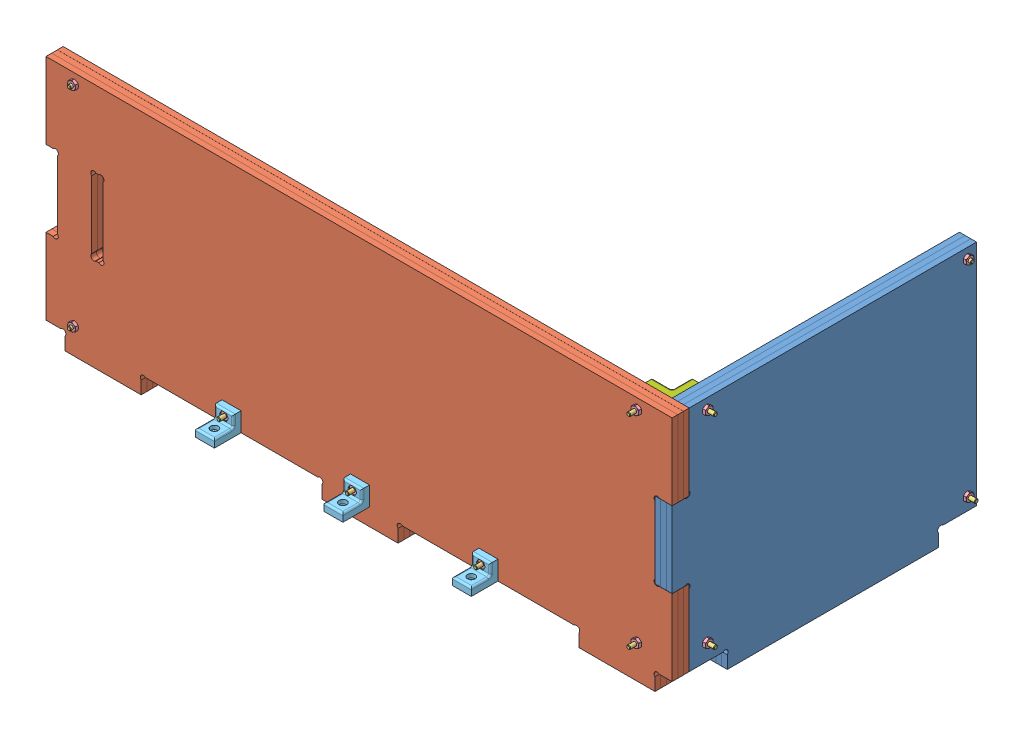
SolidWorks assembly mur-complet, configuration Défaut. Lengths in mm.
Overall size (334 129.04 174).
34 component instances, 8 part files, 87 mates.
Components (placement in the parent):
- mur_cote-1: mur_cote [Défaut] at origin size (3 129 160)
- mur_cote-2: mur_cote [Défaut] at (3 0 0) size (3 129 160)
- mur_cote-3: mur_cote [Défaut] at (6 0 0) size (3 129 160)
- grand_mur_devant-1: grand_mur_devant [Défaut] at (9 -0.0357 -3) x (-1 0 0) z (0 0 -1) size (329 129 3)
- grand_mur_devant-2: grand_mur_devant [Défaut] at (9 0 -6) x (-1 0 0) z (0 0 -1) size (329 129 3)
- grand_mur_devant-3: grand_mur_devant [Défaut] at (9 -0.0357 0) x (-1 0 0) z (0 0 -1) size (329 129 3)
- vis-chc-1: vis-chc [Vis CHC M2x12] at (-305 14 -9) x (1 0 0) z (0 1 0) size (3.8 14 3.8)
- ecrou-h-1: ecrou-h [6007 HU M2] at (-305 14 1.6) x (1 0 0) z (0 -1 0) size (4 1.6 4.62)
- vis-chc-2: vis-chc [Vis CHC M2x16] at (-9 124 -11) x (0.964192 -0.265205 0) z (0.265205 0.964192 0) size (3.8 18 3.8)
- vis-chc-3: vis-chc [Vis CHC M2x16] at (-2 124 -18) x (0 -0.924225 -0.381849) z (0 0.381849 -0.924225) size (3.8 18 3.8)
- vis-chc-4: vis-chc [Vis CHC M2x16] at (-222.5 16 -9) x (0.991602 0.129329 0) z (-0.129329 0.991602 0) size (3.8 18 3.8)
- vis-chc-5: vis-chc [Vis CHC M2x16] at (-155 16 -9) x (0.999985 0.005521 0) z (-0.005521 0.999985 0) size (3.8 18 3.8)
- vis-chc-6: vis-chc [Vis CHC M2x16] at (-87.5 16 -9) x (0.879517 -0.475868 0) z (0.475868 0.879517 0) size (3.8 18 3.8)
- ecrou-h-2: ecrou-h [6007 HU M2] at (10.6 124 -18) x (0 -0.866025 0.5) z (0 0.5 0.866025) size (4 1.6 4.62)
- ecrou-h-3: ecrou-h [6007 HU M2] at (-9 124 1.6) x (1 0 0) z (0 -1 0) size (4 1.6 4.62)
- ecrou-h-4: ecrou-h [6007 HU M2] at (-87.5 16 3.6) x (0.866025 -0.5 0) z (-0.5 -0.866025 0) size (4 1.6 4.62)
- ecrou-h-5: ecrou-h [6007 HU M2] at (-155 16 3.6) x (0.866025 -0.5 0) z (-0.5 -0.866025 0) size (4 1.6 4.62)
- ecrou-h-6: ecrou-h [6007 HU M2] at (-222.5 16 3.6) x (0 -1 0) z (-1 0 0) size (4 1.6 4.62)
- vis-chc-7: vis-chc [Vis CHC M2x16] at (-9 18 -11) x (-0.417392 -0.908727 0) z (0.908727 -0.417392 0) size (3.8 18 3.8)
- vis-chc-8: vis-chc [Vis CHC M2x16] at (-2 18 -18) x (0 -0.924225 -0.381849) z (0 0.381849 -0.924225) size (3.8 18 3.8)
- ecrou-h-7: ecrou-h [6007 HU M2] at (10.6 18 -18) x (0 0 1) z (0 1 0) size (4 1.6 4.62)
- ecrou-h-8: ecrou-h [6007 HU M2] at (-9 18 1.6) x (-1 0 0) z (0 1 0) size (4 1.6 4.62)
- equerre-ecrou-1: equerre-ecrou [Défaut] at (-222.5 8.9643 0) size (10 10 14)
- equerre-ecrou-2: equerre-ecrou [Défaut] at (-155 8.9643 0) size (10 10 14)
- equerre-ecrou-3: equerre-ecrou [Défaut] at (-87.5 8.9643 0) size (10 10 14)
- equerre-4: equerre [Défaut] at (0 9 -155) x (0 0 1) z (-1 0 0) size (10 10 14)
- coin-1: coin [Défaut] at (0 124 -9) x (0 1 0) z (-1 0 0) size (10 14 14)
- coin-tri-1: coin-tri [Défaut] at (0 9 -18) x (0 0 1) z (-1 0 0) size (14 14 14)
- vis-chc-9: vis-chc [Vis CHC M2x16] at (-2 16 -155) x (0 -0.924225 -0.381849) z (0 0.381849 -0.924225) size (3.8 18 3.8)
- vis-chc-10: vis-chc [Vis CHC M2x12] at (0 124 -155) x (0 0 -1) z (0 1 0) size (3.8 14 3.8)
- ecrou-h-9: ecrou-h [6007 HU M2] at (10.6 16 -155) x (0 0 -1) z (0 -1 0) size (4 1.6 4.62)
- ecrou-h-10: ecrou-h [6007 HU M2] at (10.6 124 -155) x (0 0 -1) z (0 -1 0) size (4 1.6 4.62)
- ecrou-h-11: ecrou-h [6007 HU M2] at (-305 124 1.6) x (1 0 0) z (0 -1 0) size (4 1.6 4.62)
- vis-chc-11: vis-chc [Vis CHC M2x12] at (-305 124 -9) x (0.964192 -0.265205 0) z (0.265205 0.964192 0) size (3.8 14 3.8)
Mates (geometry in assembly coordinates):
- Coïncidente1: coincident anti-aligned: plane of mur_cote-1 through (3 7.8686 -141.1314) normal (1 0 0); plane of mur_cote-2 through (3 7.8686 -141.1314) normal (-1 0 0)
- Coïncidente2: coincident aligned: plane of mur_cote-1 through (3 129 -9) normal (0 1 0); plane of mur_cote-2 through (6 129 -9) normal (0 1 0)
- Coïncidente3: coincident aligned: plane of mur_cote-1 through (3 91.2627 -9) normal (0 0 1); plane of mur_cote-2 through (6 91.2627 -9) normal (0 0 1)
- Coïncidente4: coincident anti-aligned: plane of mur_cote-2 through (6 7.8686 -141.1314) normal (1 0 0); plane of mur_cote-3 through (6 7.8686 -141.1314) normal (-1 0 0)
- Coïncidente5: coincident aligned: plane of mur_cote-2 through (6 129 -9) normal (0 1 0); plane of mur_cote-3 through (9 129 -9) normal (0 1 0)
- Coïncidente6: coincident aligned: plane of mur_cote-2 through (6 49 0) normal (0 0 1); plane of mur_cote-3 through (9 49 0) normal (0 0 1)
- Coïncidente25: coincident anti-aligned: plane of mur_cote-1 through (3 91.2627 -9) normal (0 0 1); plane of grand_mur_devant-2 through (1.1314 87.8686 -9) normal (0 0 -1)
- Coïncidente26: coincident aligned: plane of mur_cote-3 through (9 129 -9) normal (0 1 0); plane of grand_mur_devant-2 through (-320 129 -9) normal (0 1 0)
- Coïncidente27: coincident aligned: plane of mur_cote-3 through (9 7.8686 -141.1314) normal (1 0 0); plane of grand_mur_devant-2 through (9 129 -9) normal (1 0 0)
- Coïncidente29: coincident anti-aligned: plane of grand_mur_devant-1 through (1.1314 87.833 -6) normal (0 0 -1); plane of grand_mur_devant-2 through (1.1314 87.8686 -6) normal (0 0 1)
- Coïncidente30: coincident aligned: plane of grand_mur_devant-1 through (9 128.9643 -6) normal (1 0 0); plane of grand_mur_devant-2 through (9 129 -9) normal (1 0 0)
- Coïncidente31: coincident aligned: plane of grand_mur_devant-1 through (9 128.9643 -6) normal (1 0 0); plane of grand_mur_devant-3 through (9 128.9643 -3) normal (1 0 0)
- Coïncidente32: coincident anti-aligned: plane of grand_mur_devant-1 through (1.1314 87.833 -3) normal (0 0 1); plane of grand_mur_devant-3 through (1.1314 87.833 -3) normal (0 0 -1)
- Coïncidente33: coincident aligned: plane of grand_mur_devant-1 through (0 -0.0357 -6) normal (0 -1 0); plane of grand_mur_devant-3 through (0 -0.0357 -3) normal (0 -1 0)
- Coaxiale1: concentric anti-aligned: cylinder of grand_mur_devant-2 through (-305 14 -9) axis (0 0 1) radius 1; cylinder of vis-chc-1 through (-305 14 3) axis (0 0 -1) radius 1
- Coïncidente34: coincident anti-aligned: plane of grand_mur_devant-2 through (1.1314 87.8686 -9) normal (0 0 -1); plane of vis-chc-1 through (-305 14 -9) normal (0 0 1)
- Coaxiale2: concentric anti-aligned: cylinder of vis-chc-1 through (-305 14 3) axis (0 0 -1) radius 1; cylinder of ecrou-h-1 through (-305 14 0) axis (0 0 1) radius 0.7835
- Coïncidente35: coincident anti-aligned: plane of grand_mur_devant-3 through (1.1314 87.833 0) normal (0 0 1); plane of ecrou-h-1 through (-303 15.1547 0) normal (0 0 -1)
- Parallèle1: parallel aligned: plane of grand_mur_devant-3 through (-320 8.9643 -3) normal (-1 0 0); plane of ecrou-h-1 through (-307 15.1547 0) normal (-1 0 0)
- Coïncidente37: coincident anti-aligned: plane of grand_mur_devant-3 through (1.1314 87.833 0) normal (0 0 1); plane of equerre-ecrou-1 through (-222.5 8.9643 0) normal (0 0 -1)
- Coïncidente38: coincident anti-aligned: plane of grand_mur_devant-3 through (1.1314 87.833 0) normal (0 0 1); plane of equerre-ecrou-2 through (-155 8.9643 0) normal (0 0 -1)
- Coïncidente39: coincident anti-aligned: plane of grand_mur_devant-3 through (1.1314 87.833 0) normal (0 0 1); plane of equerre-ecrou-3 through (-87.5 8.9643 0) normal (0 0 -1)
- Coïncidente40: coincident anti-aligned: plane of mur_cote-1 through (0 7.8686 -141.1314) normal (-1 0 0); plane of equerre-4 through (0 9 -155) normal (1 0 0)
- Coaxiale3: concentric anti-aligned: cylinder of mur_cote-1 through (0 16 -155) axis (1 0 0) radius 1; cylinder of equerre-4 through (0 16 -155) axis (-1 0 0) radius 1
- Coaxiale4: concentric aligned: cylinder of grand_mur_devant-3 through (-222.5 15.9643 -3) axis (0 0 1) radius 1; cylinder of equerre-ecrou-1 through (-222.5 15.9643 0) axis (0 0 1) radius 1
- Coaxiale5: concentric aligned: cylinder of grand_mur_devant-3 through (-155 15.9643 -3) axis (0 0 1) radius 1; cylinder of equerre-ecrou-2 through (-155 15.9643 0) axis (0 0 1) radius 1
- Coaxiale6: concentric aligned: cylinder of grand_mur_devant-3 through (-87.5 15.9643 -3) axis (0 0 1) radius 1; cylinder of equerre-ecrou-3 through (-87.5 15.9643 0) axis (0 0 1) radius 1
- Coïncidente42: coincident aligned: plane of grand_mur_devant-3 through (-177.2627 8.9643 -3) normal (0 -1 0); plane of equerre-ecrou-1 through (-227.5 8.9643 4) normal (0 -1 0)
- Coïncidente43: coincident aligned: plane of grand_mur_devant-3 through (-177.2627 8.9643 -3) normal (0 -1 0); plane of equerre-ecrou-2 through (-160 8.9643 4) normal (0 -1 0)
- Coïncidente44: coincident aligned: plane of grand_mur_devant-3 through (-42.2627 8.9643 -3) normal (0 -1 0); plane of equerre-ecrou-3 through (-92.5 8.9643 4) normal (0 -1 0)
- Coïncidente45: coincident aligned: plane of mur_cote-1 through (3 9 -160) normal (0 -1 0); plane of equerre-4 through (-4 9 -160) normal (0 -1 0)
- Coïncidente46: coincident anti-aligned: plane of grand_mur_devant-2 through (1.1314 87.8686 -9) normal (0 0 -1); plane of coin-1 through (-4 119 -9) normal (0 0 1)
- Coïncidente47: coincident anti-aligned: plane of mur_cote-1 through (0 7.8686 -141.1314) normal (-1 0 0); plane of coin-1 through (0 124 -9) normal (1 0 0)
- Coïncidente49: coincident aligned: plane of mur_cote-1 through (3 129 -9) normal (0 1 0); plane of coin-1 through (-4 129 -23) normal (0 1 0)
- Coaxiale7: concentric anti-aligned: cylinder of grand_mur_devant-2 through (-222.5 16 -9) axis (0 0 1) radius 1; cylinder of vis-chc-4 through (-222.5 16 7) axis (0 0 -1) radius 1
- Coaxiale8: concentric anti-aligned: cylinder of grand_mur_devant-2 through (-155 16 -9) axis (0 0 1) radius 1; cylinder of vis-chc-5 through (-155 16 7) axis (0 0 -1) radius 1
- Coaxiale9: concentric anti-aligned: cylinder of grand_mur_devant-2 through (-87.5 16 -9) axis (0 0 1) radius 1; cylinder of vis-chc-6 through (-87.5 16 7) axis (0 0 -1) radius 1
- Coïncidente50: coincident anti-aligned: plane of grand_mur_devant-2 through (1.1314 87.8686 -9) normal (0 0 -1); plane of vis-chc-4 through (-222.5 16 -9) normal (0 0 1)
- Coïncidente51: coincident anti-aligned: plane of grand_mur_devant-2 through (1.1314 87.8686 -9) normal (0 0 -1); plane of vis-chc-5 through (-155 16 -9) normal (0 0 1)
- Coïncidente52: coincident anti-aligned: plane of grand_mur_devant-2 through (1.1314 87.8686 -9) normal (0 0 -1); plane of vis-chc-6 through (-87.5 16 -9) normal (0 0 1)
- Coaxiale10: concentric anti-aligned: cylinder of vis-chc-4 through (-222.5 16 7) axis (0 0 -1) radius 1; cylinder of ecrou-h-6 through (-222.5 16 2) axis (0 0 1) radius 0.7835
- Coaxiale11: concentric anti-aligned: cylinder of vis-chc-5 through (-155 16 7) axis (0 0 -1) radius 1; cylinder of ecrou-h-5 through (-155 16 2) axis (0 0 1) radius 0.7835
- Coaxiale12: concentric anti-aligned: cylinder of vis-chc-6 through (-87.5 16 7) axis (0 0 -1) radius 1; cylinder of ecrou-h-4 through (-87.5 16 2) axis (0 0 1) radius 0.7835
- Coïncidente53: coincident anti-aligned: plane of equerre-ecrou-1 through (-220.17 15.9643 2) normal (-0.866025 -0.5 0); plane of ecrou-h-6 through (-220.1906 16 2) normal (0.866025 0.5 0)
- Coïncidente54: coincident anti-aligned: plane of equerre-ecrou-2 through (-156.165 17.9822 2) normal (0.866025 -0.5 0); plane of ecrou-h-5 through (-156.1547 18 2) normal (-0.866025 0.5 0)
- Parallèle2: parallel anti-aligned: plane of equerre-ecrou-3 through (-86.335 13.9465 2) normal (-0.866025 0.5 0); plane of ecrou-h-4 through (-86.3453 14 2) normal (0.866025 -0.5 0)
- Coïncidente56: coincident anti-aligned: plane of equerre-ecrou-3 through (-87.5 8.9643 2) normal (0 0 1); plane of ecrou-h-4 through (-85.1906 16 2) normal (0 0 -1)
- Coïncidente57: coincident anti-aligned: plane of equerre-ecrou-2 through (-155 8.9643 2) normal (0 0 1); plane of ecrou-h-5 through (-152.6906 16 2) normal (0 0 -1)
- Coïncidente58: coincident anti-aligned: plane of equerre-ecrou-1 through (-222.5 8.9643 2) normal (0 0 1); plane of ecrou-h-6 through (-221.3453 14 2) normal (0 0 -1)
- Coaxiale13: concentric aligned: cylinder of coin-1 through (0 124 -18) axis (-1 0 0) radius 1; cylinder of vis-chc-3 through (14 124 -18) axis (-1 0 0) radius 1
- Coïncidente59: coincident anti-aligned: plane of coin-1 through (-2 124 -18) normal (-1 0 0); plane of vis-chc-3 through (-2 124 -18) normal (1 0 0)
- Coaxiale14: concentric aligned: cylinder of coin-1 through (-9 124 -9) axis (0 0 -1) radius 1; cylinder of vis-chc-2 through (-9 124 5) axis (0 0 -1) radius 1
- Coïncidente60: coincident anti-aligned: plane of coin-1 through (-9 124 -11) normal (0 0 -1); plane of vis-chc-2 through (-9 124 -11) normal (0 0 1)
- Coaxiale15: concentric anti-aligned: cylinder of vis-chc-2 through (-9 124 5) axis (0 0 -1) radius 1; cylinder of ecrou-h-3 through (-9 124 0) axis (0 0 1) radius 0.7835
- Coïncidente62: coincident anti-aligned: plane of grand_mur_devant-3 through (1.1314 87.833 0) normal (0 0 1); plane of ecrou-h-3 through (-7 125.1547 0) normal (0 0 -1)
- Parallèle4: parallel aligned: plane of grand_mur_devant-3 through (9 128.9643 -3) normal (1 0 0); plane of ecrou-h-3 through (-7 122.8453 0) normal (1 0 0)
- Coaxiale16: concentric anti-aligned: cylinder of vis-chc-3 through (14 124 -18) axis (-1 0 0) radius 1; cylinder of ecrou-h-2 through (9 124 -18) axis (1 0 0) radius 0.7835
- Coïncidente64: coincident anti-aligned: plane of mur_cote-3 through (9 7.8686 -141.1314) normal (1 0 0); plane of ecrou-h-2 through (9 121.6906 -18) normal (-1 0 0)
- Parallèle5: parallel aligned: plane of grand_mur_devant-3 through (1.1314 87.833 0) normal (0 0 1); plane of ecrou-h-2 through (9 125.1547 -16) normal (0 0 1)
- Coïncidente66: coincident anti-aligned: plane of mur_cote-1 through (0 7.8686 -141.1314) normal (-1 0 0); plane of coin-tri-1 through (0 9 -18) normal (1 0 0)
- Coïncidente67: coincident anti-aligned: plane of grand_mur_devant-2 through (1.1314 87.8686 -9) normal (0 0 -1); plane of coin-tri-1 through (0 9 -9) normal (0 0 1)
- Coïncidente69: coincident aligned: plane of mur_cote-1 through (3 9 -26.7373) normal (0 -1 0); plane of coin-tri-1 through (-4 9 -23) normal (0 -1 0)
- Coaxiale17: concentric aligned: cylinder of coin-tri-1 through (-9 18 -9) axis (0 0 -1) radius 1; cylinder of vis-chc-7 through (-9 18 5) axis (0 0 -1) radius 1
- Coïncidente70: coincident anti-aligned: plane of coin-tri-1 through (-9 18 -11) normal (0 0 -1); plane of vis-chc-7 through (-9 18 -11) normal (0 0 1)
- Coaxiale18: concentric aligned: cylinder of coin-tri-1 through (0 18 -18) axis (-1 0 0) radius 1; cylinder of vis-chc-8 through (14 18 -18) axis (-1 0 0) radius 1
- Coïncidente71: coincident anti-aligned: plane of coin-tri-1 through (-2 18 -18) normal (-1 0 0); plane of vis-chc-8 through (-2 18 -18) normal (1 0 0)
- Coaxiale19: concentric anti-aligned: cylinder of vis-chc-8 through (14 18 -18) axis (-1 0 0) radius 1; cylinder of ecrou-h-7 through (9 18 -18) axis (1 0 0) radius 0.7835
- Coïncidente72: coincident anti-aligned: plane of mur_cote-3 through (9 7.8686 -141.1314) normal (1 0 0); plane of ecrou-h-7 through (9 16.8453 -16) normal (-1 0 0)
- Parallèle6: parallel aligned: plane of grand_mur_devant-3 through (1.1314 87.833 0) normal (0 0 1); plane of ecrou-h-7 through (9 19.1547 -16) normal (0 0 1)
- Coaxiale20: concentric anti-aligned: cylinder of vis-chc-7 through (-9 18 5) axis (0 0 -1) radius 1; cylinder of ecrou-h-8 through (-9 18 0) axis (0 0 1) radius 0.7835
- Coïncidente74: coincident anti-aligned: plane of grand_mur_devant-3 through (1.1314 87.833 0) normal (0 0 1); plane of ecrou-h-8 through (-11 16.8453 0) normal (0 0 -1)
- Parallèle7: parallel aligned: plane of grand_mur_devant-3 through (9 48.9643 -3) normal (1 0 0); plane of ecrou-h-8 through (-7 16.8453 0) normal (1 0 0)
- Coaxiale21: concentric anti-aligned: cylinder of mur_cote-1 through (0 124 -155) axis (1 0 0) radius 1; cylinder of vis-chc-10 through (12 124 -155) axis (-1 0 0) radius 1
- Coïncidente76: coincident anti-aligned: plane of mur_cote-1 through (0 7.8686 -141.1314) normal (-1 0 0); plane of vis-chc-10 through (0 124 -155) normal (1 0 0)
- Coaxiale22: concentric anti-aligned: cylinder of vis-chc-10 through (12 124 -155) axis (-1 0 0) radius 1; cylinder of ecrou-h-10 through (9 124 -155) axis (1 0 0) radius 0.7835
- Coïncidente77: coincident anti-aligned: plane of mur_cote-3 through (9 7.8686 -141.1314) normal (1 0 0); plane of ecrou-h-10 through (9 125.1547 -157) normal (-1 0 0)
- Parallèle8: parallel aligned: plane of mur_cote-3 through (9 129 -160) normal (0 0 -1); plane of ecrou-h-10 through (9 122.8453 -157) normal (0 0 -1)
- Coaxiale23: concentric aligned: cylinder of equerre-4 through (0 16 -155) axis (-1 0 0) radius 1; cylinder of vis-chc-9 through (14 16 -155) axis (-1 0 0) radius 1
- Coïncidente79: coincident anti-aligned: plane of equerre-4 through (-2 16 -155) normal (-1 0 0); plane of vis-chc-9 through (-2 16 -155) normal (1 0 0)
- Coaxiale24: concentric anti-aligned: cylinder of vis-chc-9 through (14 16 -155) axis (-1 0 0) radius 1; cylinder of ecrou-h-9 through (9 16 -155) axis (1 0 0) radius 0.7835
- Coïncidente80: coincident anti-aligned: plane of mur_cote-3 through (9 7.8686 -141.1314) normal (1 0 0); plane of ecrou-h-9 through (9 17.1547 -157) normal (-1 0 0)
- Parallèle9: parallel aligned: plane of mur_cote-3 through (9 129 -160) normal (0 0 -1); plane of ecrou-h-9 through (9 14.8453 -157) normal (0 0 -1)
- Coaxiale25: concentric anti-aligned: cylinder of grand_mur_devant-2 through (-305 124 -9) axis (0 0 1) radius 1; cylinder of vis-chc-11 through (-305 124 3) axis (0 0 -1) radius 1
- Coïncidente82: coincident anti-aligned: plane of grand_mur_devant-2 through (1.1314 87.8686 -9) normal (0 0 -1); plane of vis-chc-11 through (-305 124 -9) normal (0 0 1)
- Coaxiale26: concentric anti-aligned: cylinder of ecrou-h-11 through (-305 124 0) axis (0 0 1) radius 0.7835; cylinder of vis-chc-11 through (-305 124 3) axis (0 0 -1) radius 1
- Coïncidente83: coincident anti-aligned: plane of grand_mur_devant-3 through (1.1314 87.833 0) normal (0 0 1); plane of ecrou-h-11 through (-303 125.1547 0) normal (0 0 -1)
- Parallèle10: parallel aligned: plane of grand_mur_devant-3 through (-320 88.9643 -3) normal (-1 0 0); plane of ecrou-h-11 through (-307 125.1547 0) normal (-1 0 0)
